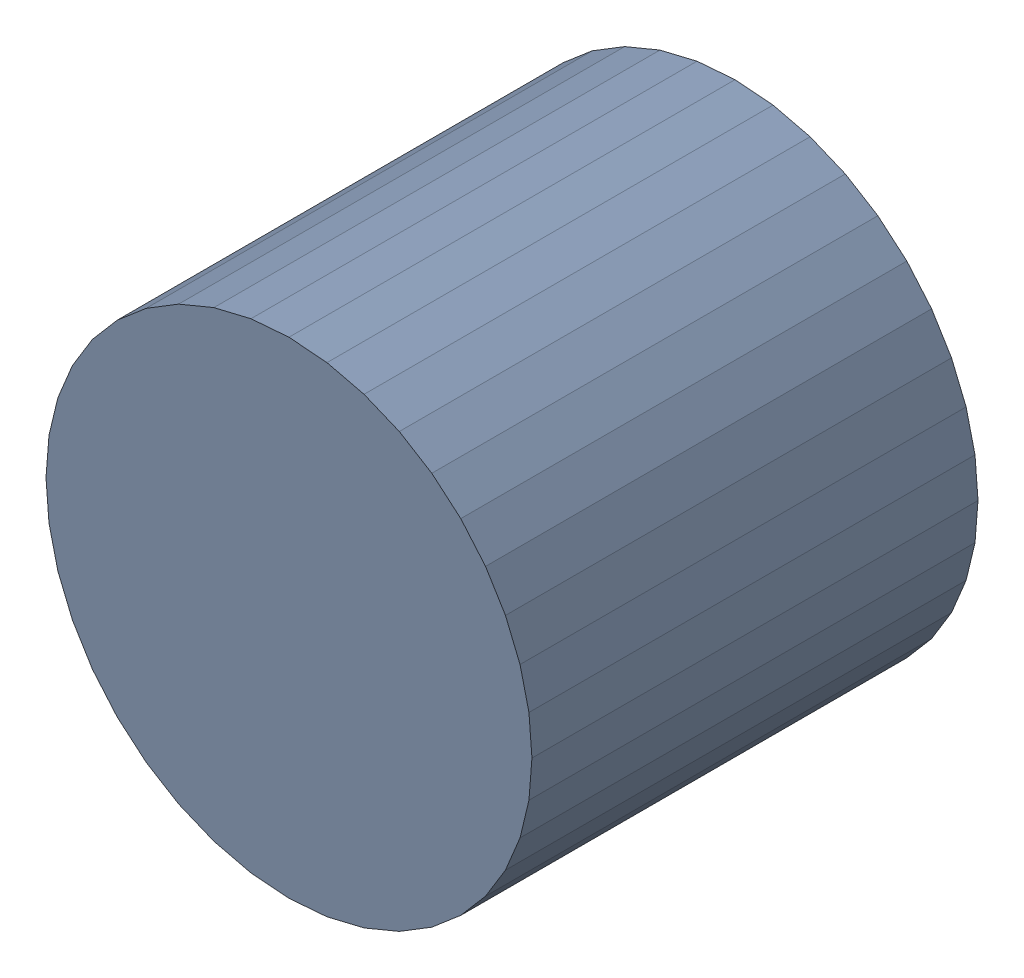
SolidWorks assembly USB67_C5, configuration Default. Lengths in mm.
Overall size (6.32 6.32 5.8).
2 component instances, 1 part files, 0 mates.
Components (placement in the parent):
- 384312384-1: 384312384 [Default] at (138.371 82.169 -6.9024) size (6.32 6.32 5.8)
  - Extruded_7-1: Extruded_7 [Default] at origin size (6.32 6.32 5.8)
